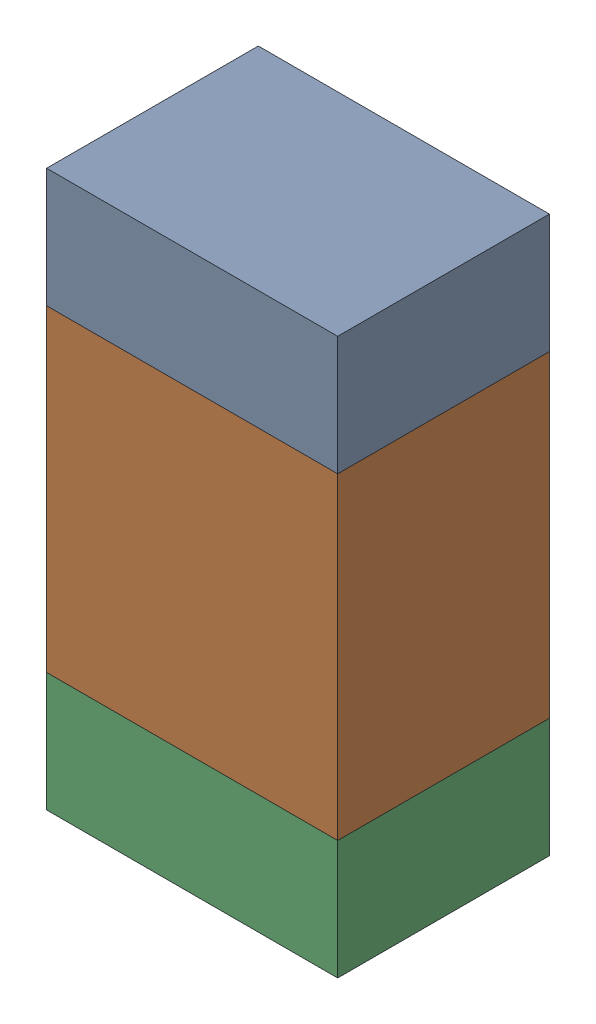
SolidWorks assembly R310_1PCB, configuration Default. Lengths in mm.
Overall size (0.55 1.05 0.4).
6 component instances, 2 part files, 0 mates.
Components (placement in the parent):
- 846483288-1: 846483288 [Default] at (134.3499 108.5469 -2.0638) size (0.55 0.22 0.4)
  - Extruded_12-1: Extruded_12 [Default] at origin size (0.55 0.22 0.4)
- 846483424-1: 846483424 [Default] at (134.3499 108.1344 -2.0638) size (0.55 0.6 0.4)
  - Extruded_13-1: Extruded_13 [Default] at origin size (0.55 0.6 0.4)
- 846483288-2: 846483288 [Default] at (134.3499 107.7219 -2.0638) size (0.55 0.22 0.4)
  - Extruded_12-1: Extruded_12 [Default] at origin size (0.55 0.22 0.4)
